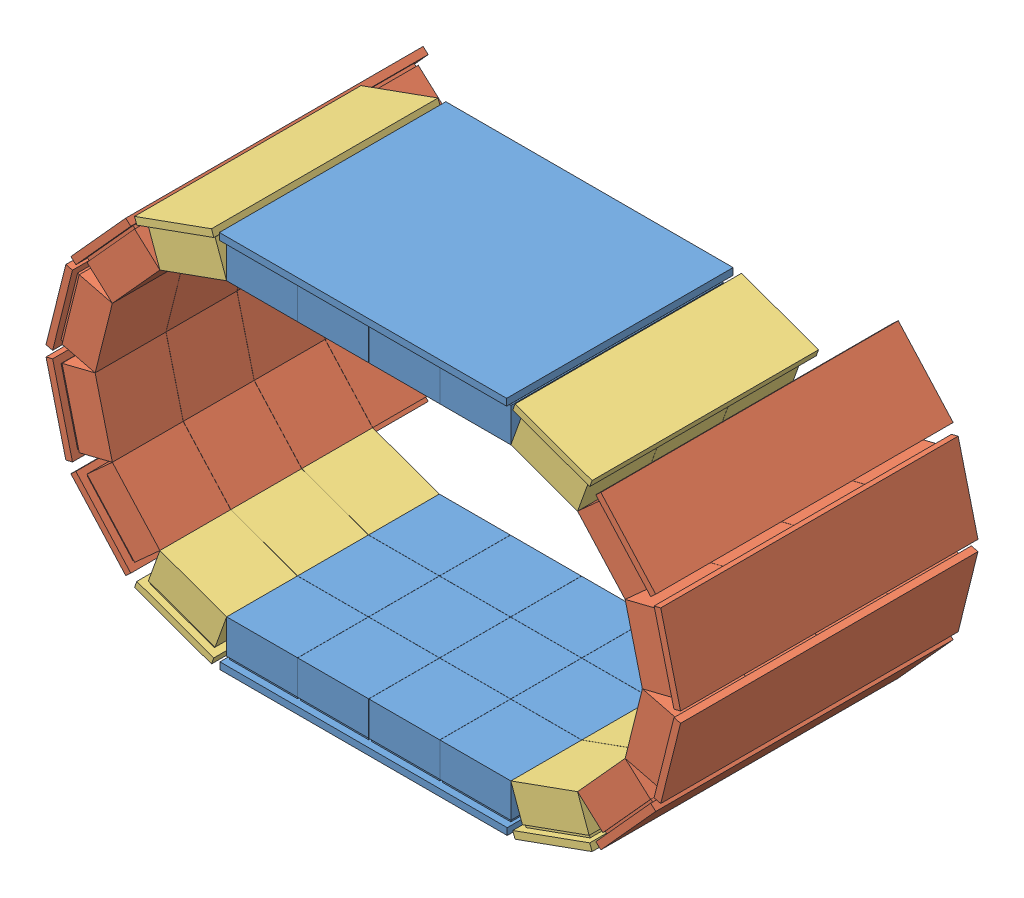
SolidWorks assembly Assem2, configuration Default. Lengths in mm.
Overall size (517.67 317.54 218).
16 component instances, 3 part files, 10 mates.
Components (placement in the parent):
- 52mmTOPBOTTOM-1: 52mmTOPBOTTOM [Default] at (-69.8528 -35.4842 8.7442) size (210.55 32 166)
- SideDetector-1: SideDetector [Default] at (215.9367 233.9438 -54.2197) x (-0.242515 0.970148 0) z (0 0 1) size (268 155.36 218)
  - 52mmX4-1: 52mmX4 [Default] at (-99.1405 6.5957 36.9639) size (60 32 218)
  - 52mmX4-2: 52mmX4 [Default] at (-35.1412 22.594 36.9639) x (0.882373 0.47055 0) z (0 0 1) size (60 32 218)
  - 52mmX4-3: 52mmX4 [Default] at (-163.1399 22.594 36.9639) x (0.882373 -0.47055 0) z (0 0 1) size (60 32 218)
  - 52mmX4-4: 52mmX4 [Default] at (-212.0831 66.8254 36.9639) x (0.557166 -0.830401 0) z (0 0 1) size (60 32 218)
  - 52mmX3-1: 52mmX3 [Default] at (-234.4563 128.8843 62.9639) x (0.100883 -0.994898 0) z (0 0 1) size (60 32 166)
  - 52mmX3-2: 52mmX3 [Default] at (13.802 66.8254 62.9639) x (0.557166 0.830401 0) z (0 0 1) size (60 32 166)
- SideDetector-2: SideDetector [Default] at (-199.3424 -27.5859 -54.2197) x (0.242515 -0.970148 0) z (0 0 1) size (268 155.36 218)
  - 52mmX4-1: 52mmX4 [Default] at (-99.1405 6.5957 36.9639) size (60 32 218)
  - 52mmX4-2: 52mmX4 [Default] at (-35.1412 22.594 36.9639) x (0.882373 0.47055 0) z (0 0 1) size (60 32 218)
  - 52mmX4-3: 52mmX4 [Default] at (-163.1399 22.594 36.9639) x (0.882373 -0.47055 0) z (0 0 1) size (60 32 218)
  - 52mmX4-4: 52mmX4 [Default] at (-212.0831 66.8254 36.9639) x (0.557166 -0.830401 0) z (0 0 1) size (60 32 218)
  - 52mmX3-1: 52mmX3 [Default] at (-234.4563 128.8843 62.9639) x (0.100883 -0.994898 0) z (0 0 1) size (60 32 166)
  - 52mmX3-2: 52mmX3 [Default] at (13.802 66.8254 62.9639) x (0.557166 0.830401 0) z (0 0 1) size (60 32 166)
- 52mmTOPBOTTOM-2: 52mmTOPBOTTOM [Default] at (86.4472 241.8421 8.7442) x (-1 0 0) z (0 0 1) size (210.55 32 166)
Mates (geometry in assembly coordinates):
- Coincident1: coincident anti-aligned: line of 52mmTOPBOTTOM-1 through (112.4472 -3.4842 87.7442) axis (0 0 -1); line of SideDetector-1/52mmX3-1 through (112.4472 -3.4842 35.8442) axis (0 0 1)
- Coincident2: coincident: point of 52mmTOPBOTTOM-1; point of SideDetector-1/52mmX3-1
- Parallel1: parallel anti-aligned: line of 52mmTOPBOTTOM-1 through (-43.7528 -3.4842 87.7442) axis (1 0 0); line of 52mmTOPBOTTOM-2 through (8.2472 209.8421 87.7442) axis (-1 0 0)
- Parallel2: parallel anti-aligned: line of 52mmTOPBOTTOM-1 through (-95.8528 -3.4842 35.8442) axis (0 0 1); line of 52mmTOPBOTTOM-2 through (-95.8528 209.8421 87.7442) axis (0 0 -1)
- Coincident5: coincident anti-aligned: line of 52mmTOPBOTTOM-1 through (-95.8528 -3.4842 35.8442) axis (0 0 1); line of SideDetector-2/52mmX3-2 through (-95.8528 -3.4842 87.7442) axis (0 0 -1)
- Coincident6: coincident: point of 52mmTOPBOTTOM-1; point of SideDetector-2/52mmX3-2
- Coincident7: coincident anti-aligned: line of SideDetector-2/52mmX3-1 through (-95.8528 209.8421 35.8442) axis (0 0 1); line of 52mmTOPBOTTOM-2 through (-95.8528 209.8421 87.7442) axis (0 0 -1)
- Coincident8: coincident anti-aligned: line of SideDetector-1/52mmX3-2 through (112.4472 209.8421 87.7442) axis (0 0 -1); line of 52mmTOPBOTTOM-2 through (112.4472 209.8421 35.8442) axis (0 0 1)
- Coincident9: coincident: point of SideDetector-2/52mmX3-1; point of 52mmTOPBOTTOM-2
- Coincident11: coincident anti-aligned: line of 52mmTOPBOTTOM-1 through (-95.8528 -3.4842 87.7442) axis (0 -1 0); line of 52mmTOPBOTTOM-2 through (-95.8528 209.8421 87.7442) axis (0 1 0)
